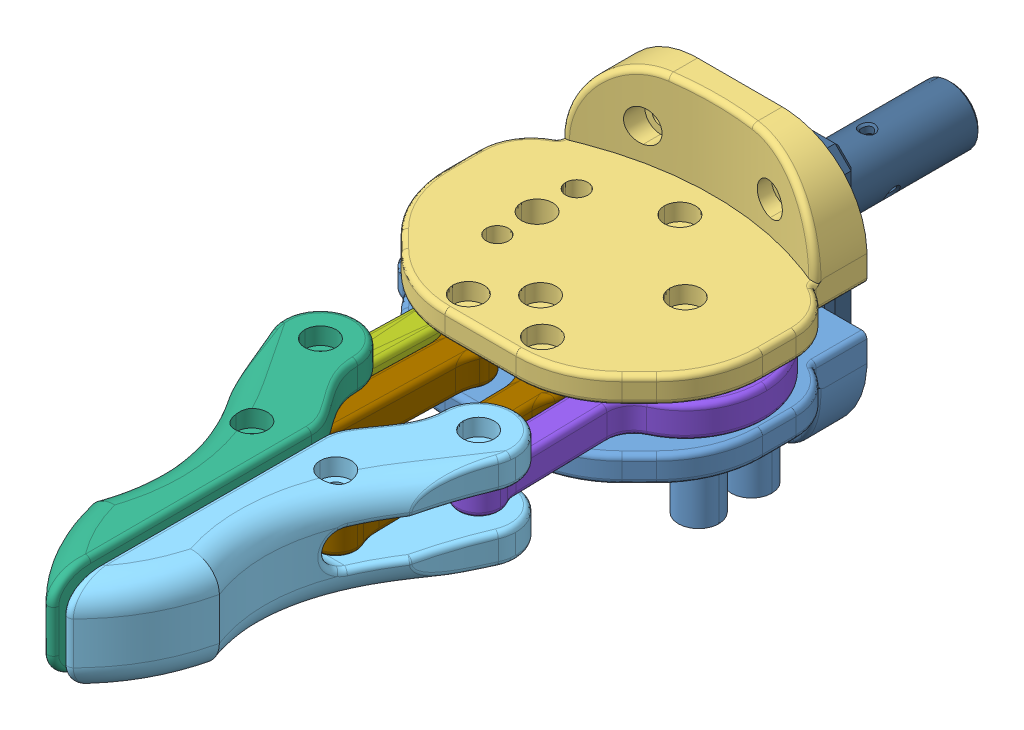
SolidWorks assembly gripper_assembly, configuration Default. Lengths in mm.
Overall size (94.5 56.93 169.45).
12 component instances, 10 part files, 20 mates.
Components (placement in the parent):
- gripper_lower_palm-1: gripper_lower_palm [Default] at (22.1329 -4.9702 60.1942) x (1 0 0) z (0 -1 0) size (63.5 49 24.46)
- gripper_motor_flange-1: gripper_motor_flange [Default] at (-3.1666 -67.0023 -38.1885) x (0 1 0) z (0.648842 0 0.760924) size (5.5 21 21)
- gripper_upper_palm-1: gripper_upper_palm [Default] at (22.1329 3.0298 60.1942) x (-1 0 0) z (0 1 0) size (60 49 24.46)
- robot_painter_02-Gripper_Assembly-gen-pt5-1: robot_painter_02-Gripper_Assembly-gen-pt5 [Default] at (-73.89 -245.9363 -141.2864) x (0.957872 0 -0.287197) z (0.287064 -0.030387 0.957429) size (7 8.21 7.24)
- robot_painter_02-Gripper_Assembly-gen-pt5-2: robot_painter_02-Gripper_Assembly-gen-pt5 [Default] at (-9.3749 -245.9363 -133.4811) x (0.999996 0 -0.002803) z (0.002802 -0.030387 0.999534) size (7 8.21 7.24)
- robot_painter_02-Gripper_Assembly-finger_pt1-1: robot_painter_02-Gripper_Assembly-finger_pt1 [Default] at (-34.0521 -247.1863 -149.8507) x (0.999999 0 0.001337) z (-0.001336 -0.030387 0.999537) size (26.22 20.13 72.07)
- robot_painter_02-Gripper_Assembly-finger_pt2-1: robot_painter_02-Gripper_Assembly-finger_pt2 [Default] at (17.0126 -247.1863 -149.3953) x (0.999999 0 -0.001337) z (0.001336 -0.030387 0.999537) size (26.22 20.09 72.06)
- robot_painter_02-Gripper_Assembly-gen-pt2-1: robot_painter_02-Gripper_Assembly-gen-pt2 [Default] at (-165.5511 -246.9363 -88.2879) x (0.752414 0 -0.658691) z (0.658386 -0.030387 0.752066) size (46.07 7.43 48.56)
- robot_painter_02-Gripper_Assembly-gen-pt4-1: robot_painter_02-Gripper_Assembly-gen-pt4 [Default] at (160.3976 -246.9363 -130.6905) x (0.761504 0 0.648161) z (-0.647861 -0.030387 0.761152) size (45.65 7.45 48.94)
- robot_painter_02-Gripper_Assembly-gen-pt3-1: robot_painter_02-Gripper_Assembly-gen-pt3 [Default] at (171.8423 -246.9363 -121.2981) x (0.76107 0 0.648669) z (-0.64837 -0.030387 0.760719) size (34.64 7.09 37.94)
- gripper_wrist-1: gripper_wrist [Default] at (22.1329 -0.9702 57.6942) size (34 40 40)
- robot_painter_02-Gripper_Assembly-gen-pt3-2: robot_painter_02-Gripper_Assembly-gen-pt3 [Default] at (156.9188 242.9959 370.2958) x (0.76107 0 -0.648669) z (-0.64837 0.030387 -0.760719) size (34.64 7.09 37.94)
Mates (geometry in assembly coordinates):
- Concentric1: concentric aligned: circle of gripper_lower_palm-1; circle of gripper_motor_flange-1
- Concentric2: concentric aligned: circle of gripper_lower_palm-1; circle of robot_painter_02-Gripper_Assembly-gen-pt5-1
- Concentric3: concentric aligned: circle of gripper_lower_palm-1; circle of robot_painter_02-Gripper_Assembly-gen-pt5-2
- Coincident1: coincident anti-aligned: plane of gripper_lower_palm-1 through (28.8529 -4.9702 89.1942) normal (0 1 0); plane of robot_painter_02-Gripper_Assembly-gen-pt5-2 through (22.1329 -4.9702 97.8542) normal (0 -1 0)
- Coincident2: coincident anti-aligned: plane of gripper_lower_palm-1 through (28.8529 -4.9702 89.1942) normal (0 1 0); plane of robot_painter_02-Gripper_Assembly-gen-pt5-1 through (22.1329 -4.9702 71.5242) normal (0 -1 0)
- Coincident5: coincident anti-aligned: plane of gripper_upper_palm-1 through (15.4129 3.0298 89.1942) normal (0 -1 0); plane of robot_painter_02-Gripper_Assembly-gen-pt5-1 through (22.1329 3.0298 71.5242) normal (0 1 0)
- Concentric4: concentric aligned: circle of gripper_upper_palm-1; circle of robot_painter_02-Gripper_Assembly-gen-pt5-1
- Concentric5: concentric aligned: circle of gripper_lower_palm-1; circle of robot_painter_02-Gripper_Assembly-gen-pt2-1
- Concentric7: concentric aligned: circle of gripper_lower_palm-1; circle of robot_painter_02-Gripper_Assembly-gen-pt3-1
- Coincident6: coincident aligned: circle of gripper_lower_palm-1; circle of robot_painter_02-Gripper_Assembly-gen-pt4-1
- Coincident7: coincident anti-aligned: circle of robot_painter_02-Gripper_Assembly-finger_pt2-1; circle of robot_painter_02-Gripper_Assembly-gen-pt2-1
- Coincident10: coincident aligned: circle of robot_painter_02-Gripper_Assembly-finger_pt1-1; circle of robot_painter_02-Gripper_Assembly-gen-pt4-1
- Coincident11: coincident aligned: circle of robot_painter_02-Gripper_Assembly-finger_pt1-1; circle of robot_painter_02-Gripper_Assembly-gen-pt3-1
- Coincident12: coincident aligned: plane of gripper_lower_palm-1 through (28.8529 -4.9702 89.1942) normal (0 1 0); circle of robot_painter_02-Gripper_Assembly-gen-pt2-1
- Concentric10: concentric aligned: circle of gripper_upper_palm-1; circle of robot_painter_02-Gripper_Assembly-gen-pt5-2
- Concentric11: concentric aligned: circle of gripper_lower_palm-1; circle of gripper_wrist-1
- Concentric12: concentric aligned: circle of gripper_upper_palm-1; circle of gripper_wrist-1
- Coincident13: coincident anti-aligned: plane of gripper_upper_palm-1 through (-1.8671 8.0298 60.1942) normal (0 0 -1); plane of gripper_wrist-1 through (22.1329 -0.9702 60.1942) normal (0 0 1)
- Concentric13: concentric anti-aligned: circle of gripper_motor_flange-1; circle of robot_painter_02-Gripper_Assembly-gen-pt2-1
- Coincident19: coincident aligned: circle of robot_painter_02-Gripper_Assembly-finger_pt2-1; circle of robot_painter_02-Gripper_Assembly-gen-pt3-2
